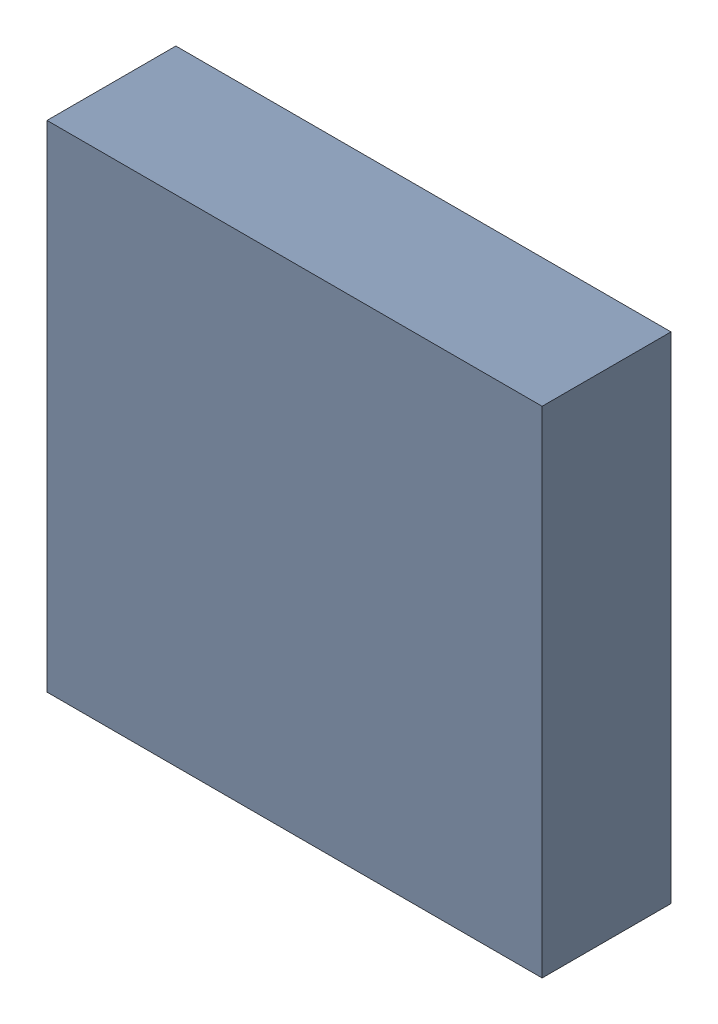
SolidWorks assembly U3, configuration Default. Lengths in mm.
Overall size (3.65 3.65 0.95).
2 component instances, 1 part files, 0 mates.
Components (placement in the parent):
- 870946080-1: 870946080 [Default] at (8.751 30.152 -2.6006) size (3.65 3.65 0.95)
  - Extruded_19-1: Extruded_19 [Default] at origin size (3.65 3.65 0.95)
